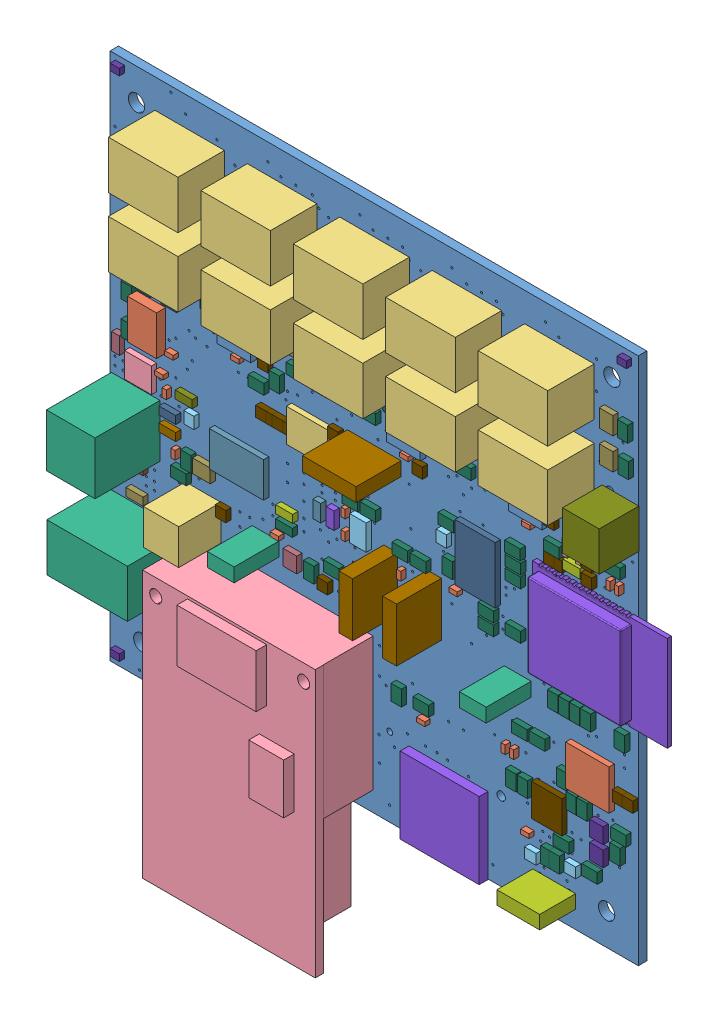
SolidWorks assembly fra_sensor_v1, configuration Default. Lengths in mm.
Overall size (107.26 121.58 17.1).
213 component instances, 44 part files, 3 mates.
Components (placement in the parent):
- fra_sensor_v1-1: fra_sensor_v1 [Default] at origin size (100 100 1.6)
- C0603K_C0603K-1: C0603K_C0603K [Default] at (46.1264 13.6398 1.6) x (-1 0 0) z (0 0 1) size (1.6 0.8 1)
- C0603K_C0603K-2: C0603K_C0603K [Default] at (75.4062 23.7998 1.6) x (0 -1 0) z (0 0 1) size (1.6 0.8 1)
- C0603K_C0603K-3: C0603K_C0603K [Default] at (77.0065 23.7998 1.6) x (0 -1 0) z (0 0 1) size (1.6 0.8 1)
- C0603K_C0603K-4: C0603K_C0603K [Default] at (56.6293 62.23 1.6) size (1.6 0.8 1)
- C0603K_C0603K-5: C0603K_C0603K [Default] at (79.4956 11.8872 1.6) x (-1 0 0) z (0 0 1) size (1.6 0.8 1)
- C0603K_C0603K-6: C0603K_C0603K [Default] at (40.9956 3.5814 1.6) size (1.6 0.8 1)
- C0603K_C0603K-7: C0603K_C0603K [Default] at (32.0865 36.9316 1.6) size (1.6 0.8 1)
- C0603K_C0603K-8: C0603K_C0603K [Default] at (40.9956 5.3467 1.6) size (1.6 0.8 1)
- C0603K_C0603K-9: C0603K_C0603K [Default] at (39.751 14.732 1.6) size (1.6 0.8 1)
- C0603K_C0603K-10: C0603K_C0603K [Default] at (39.751 16.3386 1.6) size (1.6 0.8 1)
- C0603K_C0603K-11: C0603K_C0603K [Default] at (39.751 17.9451 1.6) size (1.6 0.8 1)
- C0603K_C0603K-12: C0603K_C0603K [Default] at (28.5877 13.0175 1.6) x (-1 0 0) z (0 0 1) size (1.6 0.8 1)
- C0603K_C0603K-13: C0603K_C0603K [Default] at (22.9426 5.4229 1.6) size (1.6 0.8 1)
- C0603K_C0603K-14: C0603K_C0603K [Default] at (22.8981 3.4734 1.6) size (1.6 0.8 1)
- C0603K_C0603K-15: C0603K_C0603K [Default] at (65.913 44.7357 1.6) size (1.6 0.8 1)
- C0603K_C0603K-16: C0603K_C0603K [Default] at (21.9265 18.1292 1.6) size (1.6 0.8 1)
- C0603K_C0603K-17: C0603K_C0603K [Default] at (60.0519 69.3864 1.6) x (0 1 0) z (0 0 1) size (1.6 0.8 1)
- C0603K_C0603K-18: C0603K_C0603K [Default] at (55.6959 69.3864 1.6) x (0 1 0) z (0 0 1) size (1.6 0.8 1)
- C0603K_C0603K-19: C0603K_C0603K [Default] at (4.045 66.275 1.6) x (0 1 0) z (0 0 1) size (1.6 0.8 1)
- C0603K_C0603K-20: C0603K_C0603K [Default] at (21.1582 68.7642 1.6) x (0 1 0) z (0 0 1) size (1.6 0.8 1)
- C0603K_C0603K-21: C0603K_C0603K [Default] at (12.1349 56.6293 1.6) x (-1 0 0) z (0 0 1) size (1.6 0.8 1)
- C0603K_C0603K-22: C0603K_C0603K [Default] at (58.8391 42.3672 1.6) x (0 -1 0) z (0 0 1) size (1.6 0.8 1)
- C0603K_C0603K-23: C0603K_C0603K [Default] at (96.8565 60.4901 1.6) x (0 1 0) z (0 0 1) size (1.6 0.8 1)
- C0603K_C0603K-24: C0603K_C0603K [Default] at (95.2437 60.4901 1.6) x (0 1 0) z (0 0 1) size (1.6 0.8 1)
- C0603K_C0603K-25: C0603K_C0603K [Default] at (22.0091 14.3129 1.6) size (1.6 0.8 1)
- C0603K_C0603K-26: C0603K_C0603K [Default] at (21.952 16.3386 1.6) size (1.6 0.8 1)
- C0603K_C0603K-27: C0603K_C0603K [Default] at (12.9032 40.8305 1.6) x (0 -1 0) z (0 0 1) size (1.6 0.8 1)
- C0603K_C0603K-28: C0603K_C0603K [Default] at (55.626 42.3672 1.6) x (0 -1 0) z (0 0 1) size (1.6 0.8 1)
- C0603K_C0603K-29: C0603K_C0603K [Default] at (43.561 51.6509 1.6) x (-1 0 0) z (0 0 1) size (1.6 0.8 1)
- C0603K_C0603K-30: C0603K_C0603K [Default] at (11.2395 49.9173 1.6) x (0 -1 0) z (0 0 1) size (1.6 0.8 1)
- C0603K_C0603K-31: C0603K_C0603K [Default] at (59.8043 20.3899 1.6) x (-1 0 0) z (0 0 1) size (1.6 0.8 1)
- C0603K_C0603K-32: C0603K_C0603K [Default] at (25.2616 21.7501 1.6) x (-1 0 0) z (0 0 1) size (1.6 0.8 1)
- C0603K_C0603K-33: C0603K_C0603K [Default] at (24.7142 25.673 1.6) x (0 1 0) z (0 0 1) size (1.6 0.8 1)
- C0603K_C0603K-34: C0603K_C0603K [Default] at (10.2299 52.451 1.6) size (1.6 0.8 1)
- C0603K_C0603K-35: C0603K_C0603K [Default] at (45.1167 47.2948 1.6) x (0 -1 0) z (0 0 1) size (1.6 0.8 1)
- C0603K_C0603K-36: C0603K_C0603K [Default] at (45.1167 43.561 1.6) x (0 1 0) z (0 0 1) size (1.6 0.8 1)
- C0603K_C0603K-37: C0603K_C0603K [Default] at (79.6544 62.5412 1.6) size (1.6 0.8 1)
- C0603K_C0603K-38: C0603K_C0603K [Default] at (24.5809 62.23 1.6) size (1.6 0.8 1)
- C0603K_C0603K-39: C0603K_C0603K [Default] at (16.8021 68.7642 1.6) x (0 1 0) z (0 0 1) size (1.6 0.8 1)
- C0603K_C0603K-40: C0603K_C0603K [Default] at (27.3812 68.7642 1.6) x (0 1 0) z (0 0 1) size (1.6 0.8 1)
- C0603K_C0603K-41: C0603K_C0603K [Default] at (31.7373 68.7642 1.6) x (0 1 0) z (0 0 1) size (1.6 0.8 1)
- C0603K_C0603K-42: C0603K_C0603K [Default] at (76.2318 69.0753 1.6) x (0 1 0) z (0 0 1) size (1.6 0.8 1)
- C0603K_C0603K-43: C0603K_C0603K [Default] at (71.8756 69.0753 1.6) x (0 1 0) z (0 0 1) size (1.6 0.8 1)
- C0603K_C0603K-44: C0603K_C0603K [Default] at (82.7659 69.0753 1.6) x (0 1 0) z (0 0 1) size (1.6 0.8 1)
- C0603K_C0603K-45: C0603K_C0603K [Default] at (87.122 69.0753 1.6) x (0 1 0) z (0 0 1) size (1.6 0.8 1)
- 153CLV0605_153CLV0605-1: 153CLV0605_153CLV0605 [Default] at (17.6847 33.1724 1.6) size (6.7 6.7 8)
- C0402_C0402-1: C0402_C0402 [Default] at (87.0521 62.5475 1.6) x (0 1 0) z (0 0 1) size (2.95 0.97 1)
- C0402_C0402-2: C0402_C0402 [Default] at (89.5921 62.5475 1.6) x (0 1 0) z (0 0 1) size (2.95 0.97 1)
- SOT323R_PESD1CANSC70-1: SOT323R_PESD1CANSC70 [Default] at (80.5355 8.7969 1.6) x (0 -1 0) z (0 0 1) size (1.92 2.2 1)
- SOT323R_PESD1CANSC70-2: SOT323R_PESD1CANSC70 [Default] at (88.0358 10.2531 1.6) x (0 1 0) z (0 0 1) size (1.92 2.2 1)
- SOT323R_PESD1CANSC70-3: SOT323R_PESD1CANSC70 [Default] at (15.9449 47.9235 1.6) x (-1 0 0) z (0 0 1) size (1.92 2.2 1)
- SOT323R_PESD1CANSC70-4: SOT323R_PESD1CANSC70 [Default] at (63.6651 52.3811 1.6) size (1.92 2.2 1)
- 1X02_1X02-1: 1X02_1X02 [Default] at (29.4386 34.3598 1.6) x (-1 0 0) z (0 0 1) size (5.08 2.62 8.5)
- 1X02_1X02-2: 1X02_1X02 [Default] at (77.1652 35.16 1.6) size (5.08 2.62 8.5)
- 0603_FB1_0603-1: 0603_FB1_0603 [Default] at (33.9514 41.5231 1.6) size (3.2 1.48 1)
- 0603_FB2_0603-1: 0603_FB2_0603 [Default] at (42.6657 45.1528 1.6) x (0 1 0) z (0 0 1) size (3.2 1.48 1)
- 0603_FB3_0603-1: 0603_FB3_0603 [Default] at (11.8237 43.8721 1.6) size (3.2 1.48 1)
- 0603_FB4_0603-1: 0603_FB4_0603 [Default] at (11.8237 46.6725 1.6) size (3.2 1.48 1)
- 0603_FB5_0603-1: 0603_FB5_0603 [Default] at (5.6007 35.16 1.6) size (3.2 1.48 1)
- 0603_FB6_0603-1: 0603_FB6_0603 [Default] at (5.6007 30.1816 1.6) size (3.2 1.48 1)
- 0603_FB7_0603-1: 0603_FB7_0603 [Default] at (2.0447 53.5559 1.6) x (0 1 0) z (0 0 1) size (3.2 1.48 1)
- 0603_FB8_0603-1: 0603_FB8_0603 [Default] at (40.1384 45.1167 1.6) x (0 1 0) z (0 0 1) size (3.2 1.48 1)
- 0603_FB9_0603-1: 0603_FB9_0603 [Default] at (33.9153 39.2049 1.6) size (3.2 1.48 1)
- 0603_FB10_0603-1: 0603_FB10_0603 [Default] at (14.9352 50.8419 1.6) x (-1 0 0) z (0 0 1) size (3.2 1.48 1)
- FIDUCIAL_1MM_FIDUCIAL__-1: FIDUCIAL_1MM_FIDUCIAL__ [Default] at (2 98 1.6) size (1.75 1.25 1)
- FIDUCIAL_1MM_FIDUCIAL__-2: FIDUCIAL_1MM_FIDUCIAL__ [Default] at (98 98 1.6) size (1.75 1.25 1)
- FIDUCIAL_1MM_FIDUCIAL__-3: FIDUCIAL_1MM_FIDUCIAL__ [Default] at (2 2 1.6) size (1.75 1.25 1)
- MLP28_CP2101-1: MLP28_CP2101 [Default] at (83.82 18.0975 1.6) x (0 1 0) z (0 0 1) size (6.1 5.78 1)
- SOP50P490X11010N_1100000_ADS1115IDGSR_1100000-1: SOP50P490X11010N_1100000_ADS1115IDGSR_1100000 [Default] at (56.6293 65.0303 1.6) x (-1 0 0) z (0 0 1) size (6.35 3.62 1.1)
- SOP50P490X11010N_1100000_ADS1115IDGSR_1100000-2: SOP50P490X11010N_1100000_ADS1115IDGSR_1100000 [Default] at (79.6989 65.2399 1.6) x (-1 0 0) z (0 0 1) size (6.35 3.62 1.1)
- SOP50P490X11010N_1100000_ADS1115IDGSR_1100000-3: SOP50P490X11010N_1100000_ADS1115IDGSR_1100000 [Default] at (24.5364 65.0875 1.6) x (-1 0 0) z (0 0 1) size (6.35 3.62 1.1)
- SOIC127P600X1758N_1750000_P82B715DR_1750000-1: SOIC127P600X1758N_1750000_P82B715DR_1750000 [Default] at (7.7788 59.4297 1.6) x (0 1 0) z (0 0 1) size (7.5 5.53 1.75)
- TSSOP24_PCA9555PW-1: TSSOP24_PCA9555PW [Default] at (38.2715 56.3181 1.6) x (-1 0 0) z (0 0 1) size (7.78 6.24 1)
- STSOT89_LDK320ADU50R-1: STSOT89_LDK320ADU50R [Default] at (6.1468 50.8889 1.6) x (0 1 0) z (0 0 1) size (4.7 5.09 1)
- 2X6_ETH_CONN-1: 2X6_ETH_CONN [Default] at (27.305 26.67 0) x (1 0 0) z (0 0 -1) size (15.34 5.46 1)
- PJ059A_11000000_PJ059A_11000000-1: PJ059A_11000000_PJ059A_11000000 [Default] at (10.5791 23.6474 1.6) size (15.25 9.05 11)
- USBBMICROSMD_VERT_WM9734TRND-1: USBBMICROSMD_VERT_WM9734TRND [Default] at (84.1285 5.2407 1.6) size (8.1 2.55 6.8)
- 1140084168_1680000_1140084168_1680000-1: 1140084168_1680000_1140084168_1680000 [Default] at (64.0771 7.1336 1.6) size (14.95 14.45 1.68)
- 1X04_1X04-1: 1X04_1X04 [Default] at (50 59 1.6) size (10.16 2.62 8.5)
- 1X04_1X04-2: 1X04_1X04 [Default] at (61.3791 39.8272 1.6) x (0 -1 0) z (0 0 1) size (10.16 2.62 8.5)
- 1X04_1X04-3: 1X04_1X04 [Default] at (53.086 39.8272 1.6) x (0 -1 0) z (0 0 1) size (10.16 2.62 8.5)
- 2X05_1_27MM_SMT_DNI-1: 2X05_1_27MM_SMT_DNI [Default] at (70.2922 51.4515 1.6) x (0 -1 0) z (0 0 1) size (10.74 7.6 1)
- SRP5030CA_SRP5030CA1R5M-1: SRP5030CA_SRP5030CA1R5M [Default] at (36.1696 9.1821 1.6) x (-1 0 0) z (0 0 1) size (5.47 5.58 1)
- SRP5030CA_SRP5030CA1R5M-2: SRP5030CA_SRP5030CA1R5M [Default] at (18.0086 8.9726 1.6) x (-1 0 0) z (0 0 1) size (5.47 5.58 1)
- SOT23WIDE_FDN306P-1: SOT23WIDE_FDN306P [Default] at (18.2816 40.786 1.6) size (3.35 2.59 1)
- SOT23WIDE_FDN306P-2: SOT23WIDE_FDN306P [Default] at (7.1564 69.1868 1.6) size (3.35 2.59 1)
- SOT23WIDE_FDN306P-3: SOT23WIDE_FDN306P [Default] at (12.1349 69.1868 1.6) size (3.35 2.59 1)
- SOT23WIDE_FDN306P-4: SOT23WIDE_FDN306P [Default] at (40.4806 69.3735 1.6) size (3.35 2.59 1)
- SOT23WIDE_FDN306P-5: SOT23WIDE_FDN306P [Default] at (35.7823 69.3864 1.6) size (3.35 2.59 1)
- SOT23WIDE_FDN306P-6: SOT23WIDE_FDN306P [Default] at (63.1634 69.1868 1.6) size (3.35 2.59 1)
- SOT23WIDE_FDN306P-7: SOT23WIDE_FDN306P [Default] at (67.7062 69.1686 1.6) size (3.35 2.59 1)
- SOT23WIDE_FDN306P-8: SOT23WIDE_FDN306P [Default] at (94.9008 87.122 1.6) x (0 1 0) z (0 0 1) size (3.35 2.59 1)
- SOT23WIDE_FDN306P-9: SOT23WIDE_FDN306P [Default] at (94.9008 81.2101 1.6) x (0 1 0) z (0 0 1) size (3.35 2.59 1)
- SOT23WIDE_FDN306P-10: SOT23WIDE_FDN306P [Default] at (45.1167 69.3864 1.6) size (3.35 2.59 1)
- SOT23WIDE_FDN306P-11: SOT23WIDE_FDN306P [Default] at (49.784 69.3864 1.6) size (3.35 2.59 1)
- SOT23_SI2300DS-1: SOT23_SI2300DS [Default] at (35.0393 34.3345 1.6) x (0 1 0) z (0 0 1) size (2.92 2.59 1)
- TO252_DNI-1: TO252_DNI [Default] at (24.892 45.1167 1.6) x (0 1 0) z (0 0 1) size (6.66 10.26 1)
- R0603_R0603-1: R0603_R0603 [Default] at (97.1804 20.212 1.6) x (-1 0 0) z (0 0 1) size (2.95 1.97 1)
- R0603_R0603-2: R0603_R0603 [Default] at (96.5454 17.0371 1.6) x (0 -1 0) z (0 0 1) size (2.95 1.97 1)
- R0603_R0603-3: R0603_R0603 [Default] at (76.8477 19.3675 1.6) x (0 -1 0) z (0 0 1) size (2.95 1.97 1)
- R0603_R0603-4: R0603_R0603 [Default] at (79.0639 19.3675 1.6) x (0 -1 0) z (0 0 1) size (2.95 1.97 1)
- R0603_R0603-5: R0603_R0603 [Default] at (85.081 10.0032 1.6) x (0 1 0) z (0 0 1) size (2.95 1.97 1)
- R0603_R0603-6: R0603_R0603 [Default] at (83.4935 10.0032 1.6) x (0 1 0) z (0 0 1) size (2.95 1.97 1)
- R0603_R0603-7: R0603_R0603 [Default] at (86.4616 24.2945 1.6) x (0 1 0) z (0 0 1) size (2.95 1.97 1)
- R0603_R0603-8: R0603_R0603 [Default] at (64.5668 55.4291 1.6) x (-1 0 0) z (0 0 1) size (2.95 1.97 1)
- R0603_R0603-9: R0603_R0603 [Default] at (84.4804 61.068 1.6) size (2.95 1.97 1)
- R0603_R0603-10: R0603_R0603 [Default] at (77.1652 57.1627 1.6) size (2.95 1.97 1)
- R0603_R0603-11: R0603_R0603 [Default] at (28.5305 11.1252 1.6) x (-1 0 0) z (0 0 1) size (2.95 1.97 1)
- R0603_R0603-12: R0603_R0603 [Default] at (77.2414 43.688 1.6) size (2.95 1.97 1)
- R0603_R0603-13: R0603_R0603 [Default] at (77.216 52.6034 1.6) size (2.95 1.97 1)
- R0603_R0603-14: R0603_R0603 [Default] at (91.4781 65.6527 1.6) size (2.95 1.97 1)
- R0603_R0603-15: R0603_R0603 [Default] at (57.8739 69.3864 1.6) x (0 1 0) z (0 0 1) size (2.95 1.97 1)
- R0603_R0603-16: R0603_R0603 [Default] at (46.1264 11.8745 1.6) x (-1 0 0) z (0 0 1) size (2.95 1.97 1)
- R0603_R0603-17: R0603_R0603 [Default] at (88.9254 36.2331 1.6) x (0 -1 0) z (0 0 1) size (2.95 1.97 1)
- R0603_R0603-18: R0603_R0603 [Default] at (53.5178 69.3864 1.6) x (0 1 0) z (0 0 1) size (2.95 1.97 1)
- R0603_R0603-19: R0603_R0603 [Default] at (78.4924 28.2004 1.6) size (2.95 1.97 1)
- R0603_R0603-20: R0603_R0603 [Default] at (42.8561 36.7792 1.6) x (-1 0 0) z (0 0 1) size (2.95 1.97 1)
- R0603_R0603-21: R0603_R0603 [Default] at (38.5889 34.309 1.6) x (0 1 0) z (0 0 1) size (2.95 1.97 1)
- R0603_R0603-22: R0603_R0603 [Default] at (37.7628 3.5808 1.6) size (2.95 1.97 1)
- R0603_R0603-23: R0603_R0603 [Default] at (81.8174 28.2665 1.6) size (2.95 1.97 1)
- R0603_R0603-24: R0603_R0603 [Default] at (77.2287 54.8703 1.6) size (2.95 1.97 1)
- R0603_R0603-25: R0603_R0603 [Default] at (64.8398 48.1647 1.6) x (0 1 0) z (0 0 1) size (2.95 1.97 1)
- R0603_R0603-26: R0603_R0603 [Default] at (55.8355 46.1709 1.6) x (-1 0 0) z (0 0 1) size (2.95 1.97 1)
- R0603_R0603-27: R0603_R0603 [Default] at (59.2899 46.1328 1.6) size (2.95 1.97 1)
- R0603_R0603-28: R0603_R0603 [Default] at (46.5963 8.8836 1.6) size (2.95 1.97 1)
- R0603_R0603-29: R0603_R0603 [Default] at (46.5963 6.7627 1.6) size (2.95 1.97 1)
- R0603_R0603-30: R0603_R0603 [Default] at (46.5963 4.6387 1.6) size (2.95 1.97 1)
- R0603_R0603-31: R0603_R0603 [Default] at (90.9892 36.2585 1.6) x (0 -1 0) z (0 0 1) size (2.95 1.97 1)
- R0603_R0603-32: R0603_R0603 [Default] at (72.1106 42.1894 1.6) x (-1 0 0) z (0 0 1) size (2.95 1.97 1)
- R0603_R0603-33: R0603_R0603 [Default] at (4.045 56.6293 1.6) x (0 1 0) z (0 0 1) size (2.95 1.97 1)
- R0603_R0603-34: R0603_R0603 [Default] at (4.045 62.8523 1.6) x (0 -1 0) z (0 0 1) size (2.95 1.97 1)
- R0603_R0603-35: R0603_R0603 [Default] at (32.0485 62.23 1.6) x (0 1 0) z (0 0 1) size (2.95 1.97 1)
- R0603_R0603-36: R0603_R0603 [Default] at (28.6258 60.0519 1.6) size (2.95 1.97 1)
- R0603_R0603-37: R0603_R0603 [Default] at (42.9387 24.5809 1.6) x (0 1 0) z (0 0 1) size (2.95 1.97 1)
- R0603_R0603-38: R0603_R0603 [Default] at (88.265 21.2725 1.6) x (0 -1 0) z (0 0 1) size (2.95 1.97 1)
- R0603_R0603-39: R0603_R0603 [Default] at (86.36 13.6525 1.6) size (2.95 1.97 1)
- R0603_R0603-40: R0603_R0603 [Default] at (91.7512 11.4363 1.6) x (-1 0 0) z (0 0 1) size (2.95 1.97 1)
- R0603_R0603-41: R0603_R0603 [Default] at (90.3256 21.2852 1.6) x (0 -1 0) z (0 0 1) size (2.95 1.97 1)
- R0603_R0603-42: R0603_R0603 [Default] at (72.1106 44.4691 1.6) x (-1 0 0) z (0 0 1) size (2.95 1.97 1)
- R0603_R0603-43: R0603_R0603 [Default] at (97.4154 35.9474 1.6) x (0 -1 0) z (0 0 1) size (2.95 1.97 1)
- R0603_R0603-44: R0603_R0603 [Default] at (19.3675 3.4925 1.6) size (2.95 1.97 1)
- R0603_R0603-45: R0603_R0603 [Default] at (28.3464 8.2486 1.6) size (2.95 1.97 1)
- R0603_R0603-46: R0603_R0603 [Default] at (28.3407 4.0488 1.6) size (2.95 1.97 1)
- R0603_R0603-47: R0603_R0603 [Default] at (28.3477 6.1652 1.6) size (2.95 1.97 1)
- R0603_R0603-48: R0603_R0603 [Default] at (13.9446 37.865 1.6) x (-1 0 0) z (0 0 1) size (2.95 1.97 1)
- R0603_R0603-49: R0603_R0603 [Default] at (15.3162 40.8305 1.6) x (0 -1 0) z (0 0 1) size (2.95 1.97 1)
- R0603_R0603-50: R0603_R0603 [Default] at (86.8489 36.2331 1.6) x (0 -1 0) z (0 0 1) size (2.95 1.97 1)
- R0603_R0603-51: R0603_R0603 [Default] at (84.7789 36.2331 1.6) x (0 -1 0) z (0 0 1) size (2.95 1.97 1)
- R0603_R0603-52: R0603_R0603 [Default] at (55.1752 22.4536 1.6) x (0 1 0) z (0 0 1) size (2.95 1.97 1)
- R0603_R0603-53: R0603_R0603 [Default] at (59.817 22.8409 1.6) x (-1 0 0) z (0 0 1) size (2.95 1.97 1)
- R0603_R0603-54: R0603_R0603 [Default] at (7.1564 65.3415 1.6) x (-1 0 0) z (0 0 1) size (2.95 1.97 1)
- R0603_R0603-55: R0603_R0603 [Default] at (96.0692 63.4556 1.6) x (-1 0 0) z (0 0 1) size (2.95 1.97 1)
- R0603_R0603-56: R0603_R0603 [Default] at (12.1349 65.3415 1.6) x (-1 0 0) z (0 0 1) size (2.95 1.97 1)
- R0603_R0603-57: R0603_R0603 [Default] at (40.4495 65.5412 1.6) x (-1 0 0) z (0 0 1) size (2.95 1.97 1)
- R0603_R0603-58: R0603_R0603 [Default] at (35.7823 65.6527 1.6) x (-1 0 0) z (0 0 1) size (2.95 1.97 1)
- R0603_R0603-59: R0603_R0603 [Default] at (63.1634 65.6527 1.6) x (-1 0 0) z (0 0 1) size (2.95 1.97 1)
- R0603_R0603-60: R0603_R0603 [Default] at (67.8307 65.6527 1.6) x (-1 0 0) z (0 0 1) size (2.95 1.97 1)
- R0603_R0603-61: R0603_R0603 [Default] at (98.0122 87.122 1.6) x (0 -1 0) z (0 0 1) size (2.95 1.97 1)
- R0603_R0603-62: R0603_R0603 [Default] at (98.1238 81.2101 1.6) x (0 -1 0) z (0 0 1) size (2.95 1.97 1)
- R0603_R0603-63: R0603_R0603 [Default] at (45.1167 65.6527 1.6) x (-1 0 0) z (0 0 1) size (2.95 1.97 1)
- R0603_R0603-64: R0603_R0603 [Default] at (49.784 65.6527 1.6) x (-1 0 0) z (0 0 1) size (2.95 1.97 1)
- R0603_R0603-65: R0603_R0603 [Default] at (46.3614 49.784 1.6) size (2.95 1.97 1)
- R0603_R0603-66: R0603_R0603 [Default] at (49.784 49.784 1.6) x (-1 0 0) z (0 0 1) size (2.95 1.97 1)
- R0603_R0603-67: R0603_R0603 [Default] at (23.3362 68.7642 1.6) x (0 1 0) z (0 0 1) size (2.95 1.97 1)
- R0603_R0603-68: R0603_R0603 [Default] at (18.9802 68.7642 1.6) x (0 1 0) z (0 0 1) size (2.95 1.97 1)
- R0603_R0603-69: R0603_R0603 [Default] at (25.5143 68.7642 1.6) x (0 1 0) z (0 0 1) size (2.95 1.97 1)
- R0603_R0603-70: R0603_R0603 [Default] at (29.5592 68.7642 1.6) x (0 1 0) z (0 0 1) size (2.95 1.97 1)
- R0603_R0603-71: R0603_R0603 [Default] at (78.4098 69.0753 1.6) x (0 1 0) z (0 0 1) size (2.95 1.97 1)
- R0603_R0603-72: R0603_R0603 [Default] at (74.0537 69.0753 1.6) x (0 1 0) z (0 0 1) size (2.95 1.97 1)
- R0603_R0603-73: R0603_R0603 [Default] at (80.5879 69.0753 1.6) x (0 1 0) z (0 0 1) size (2.95 1.97 1)
- R0603_R0603-74: R0603_R0603 [Default] at (84.944 69.0753 1.6) x (0 1 0) z (0 0 1) size (2.95 1.97 1)
- B3F31XX_S1_B3F31XX-1: B3F31XX_S1_B3F31XX [Default] at (95.8977 71.6597 1.6) x (0 1 0) z (0 0 1) size (7.44 6.93 7.5)
- SOT23_BC847-1: SOT23_BC847 [Default] at (93.0529 18.942 1.6) x (0 1 0) z (0 0 1) size (2.92 2.59 1)
- SOT23_BC847-2: SOT23_BC847 [Default] at (93.0529 15.132 1.6) x (0 1 0) z (0 0 1) size (2.92 2.59 1)
- TP10R_TPTP10R-1: TP10R_TPTP10R [Default] at (35.3758 3.6004 1.6) size (2 2 1)
- TP10R_TPTP10R-2: TP10R_TPTP10R [Default] at (36.6141 16.4275 1.6) size (2 2 1)
- TP10R_TPTP10R-3: TP10R_TPTP10R [Default] at (18.4595 16.6306 1.6) size (2 2 1)
- TP10R_TPTP10R-4: TP10R_TPTP10R [Default] at (17.3228 3.5179 1.6) size (2 2 1)
- TP10R_TPTP10R-5: TP10R_TPTP10R [Default] at (41.1544 33.3439 1.6) size (2 2 1)
- TP10R_TPTP10R-6: TP10R_TPTP10R [Default] at (91.1669 59.1185 1.6) size (2 2 1)
- TP10R_TPTP10R-7: TP10R_TPTP10R [Default] at (91.1669 61.9188 1.6) size (2 2 1)
- TP10R_TPTP10R-8: TP10R_TPTP10R [Default] at (85.5662 59.1185 1.6) size (2 2 1)
- TP10R_TPTP10R-9: TP10R_TPTP10R [Default] at (84.0105 59.1185 1.6) size (2 2 1)
- TP10R_TPTP10R-10: TP10R_TPTP10R [Default] at (29.8704 64.0969 1.6) size (2 2 1)
- TP10R_TPTP10R-11: TP10R_TPTP10R [Default] at (21.9012 35.56 1.6) size (2 2 1)
- TP10R_TPTP10R-12: TP10R_TPTP10R [Default] at (84.0105 65.3415 1.6) size (2 2 1)
- TP10R_TPTP10R-13: TP10R_TPTP10R [Default] at (43.1609 59.0677 1.6) size (2 2 1)
- TP10R_TPTP10R-14: TP10R_TPTP10R [Default] at (29.5592 55.6959 1.6) size (2 2 1)
- TP10R_TPTP10R-15: TP10R_TPTP10R [Default] at (31.115 55.6959 1.6) size (2 2 1)
- TP10R_TPTP10R-16: TP10R_TPTP10R [Default] at (32.6707 55.6959 1.6) size (2 2 1)
- TP10R_TPTP10R-17: TP10R_TPTP10R [Default] at (34.2265 55.6959 1.6) size (2 2 1)
- TP10R_TPTP10R-18: TP10R_TPTP10R [Default] at (97.0788 26.4477 1.6) size (2 2 1)
- TP10R_TPTP10R-19: TP10R_TPTP10R [Default] at (98.9457 26.4477 1.6) size (2 2 1)
- TP10R_TPTP10R-20: TP10R_TPTP10R [Default] at (59.1185 61.2965 1.6) size (2 2 1)
- SOT236_TPS563249DDCR-1: SOT236_TPS563249DDCR [Default] at (24.3586 9.9886 1.6) x (0 -1 0) z (0 0 1) size (2.97 3 1)
- SOT236_TPS563249DDCR-2: SOT236_TPS563249DDCR [Default] at (42.2593 10.3441 1.6) x (0 -1 0) z (0 0 1) size (2.97 3 1)
- 2X03_1_27MM_SMT_DNI-1: 2X03_1_27MM_SMT_DNI [Default] at (91.3448 26.8161 1.6) x (-1 0 0) z (0 0 1) size (8.2 7.6 1)
- WE_61200621621_CONN_03X2_WE_61200621621-1: WE_61200621621_CONN_03X2_WE_61200621621 [Default] at (15 90 1.6) x (0 -1 0) z (0 0 1) size (9.1 13.16 8.8)
- WE_61200621621_CONN_03X2_WE_61200621621-2: WE_61200621621_CONN_03X2_WE_61200621621 [Default] at (15 77 1.6) x (0 -1 0) z (0 0 1) size (9.1 13.16 8.8)
- WE_61200621621_CONN_03X2_WE_61200621621-3: WE_61200621621_CONN_03X2_WE_61200621621 [Default] at (32.5 90 1.6) x (0 -1 0) z (0 0 1) size (9.1 13.16 8.8)
- WE_61200621621_CONN_03X2_WE_61200621621-4: WE_61200621621_CONN_03X2_WE_61200621621 [Default] at (32.5 77 1.6) x (0 -1 0) z (0 0 1) size (9.1 13.16 8.8)
- WE_61200621621_CONN_03X2_WE_61200621621-5: WE_61200621621_CONN_03X2_WE_61200621621 [Default] at (67.5 90 1.6) x (0 -1 0) z (0 0 1) size (9.1 13.16 8.8)
- WE_61200621621_CONN_03X2_WE_61200621621-6: WE_61200621621_CONN_03X2_WE_61200621621 [Default] at (67.5 77 1.6) x (0 -1 0) z (0 0 1) size (9.1 13.16 8.8)
- WE_61200621621_CONN_03X2_WE_61200621621-7: WE_61200621621_CONN_03X2_WE_61200621621 [Default] at (85 90 1.6) x (0 -1 0) z (0 0 1) size (9.1 13.16 8.8)
- WE_61200621621_CONN_03X2_WE_61200621621-8: WE_61200621621_CONN_03X2_WE_61200621621 [Default] at (85 77 1.6) x (0 -1 0) z (0 0 1) size (9.1 13.16 8.8)
- WE_61200621621_CONN_03X2_WE_61200621621-9: WE_61200621621_CONN_03X2_WE_61200621621 [Default] at (50 90 1.6) x (0 -1 0) z (0 0 1) size (9.1 13.16 8.8)
- WE_61200621621_CONN_03X2_WE_61200621621-10: WE_61200621621_CONN_03X2_WE_61200621621 [Default] at (50 77 1.6) x (0 -1 0) z (0 0 1) size (9.1 13.16 8.8)
- ETH_MODULE_OUTLINE_SMALL_ETH_MODULE_OUTLINE-1: ETH_MODULE_OUTLINE_SMALL_ETH_MODULE_OUTLINE [Default] at (17.145 -21.59 1.6) size (32.7 50.55 17.1)
- SOT5051_PCA9509DP-1: SOT5051_PCA9509DP [Default] at (47.9171 45.4279 1.6) size (3.13 4.8 1)
- W237102_W237102-1: W237102_W237102 [Default] at (5.715 42.4307 1.6) x (0 -1 0) z (0 0 1) size (9.98 9.2 12.3)
- CRYSTALSMD3_2X1_5MM_DNI-1: CRYSTALSMD3_2X1_5MM_DNI [Default] at (88.3222 59.69 1.6) size (3.33 1.7 1)
- esp32wroom-1: esp32wroom [Default] at (93.54 52.6943 1.6) x (0 -1 0) z (-1 0 0) size (18.01 2.81 25.51)
Mates (geometry in assembly coordinates):
- Coincident1: coincident anti-aligned: plane of fra_sensor_v1-1 through (0 0 1.6) normal (0 0 1); plane of esp32wroom-1 through (93.54 52.6943 1.6) normal (0 0 -1)
- Parallel1: parallel aligned: plane of fra_sensor_v1-1 through (100 0 1.6) normal (1 0 0); plane of esp32wroom-1 through (106.29 57.1943 2.4) normal (1 0 0)
- Lock3: lock: unknown of fra_sensor_v1-1; unknown of esp32wroom-1
